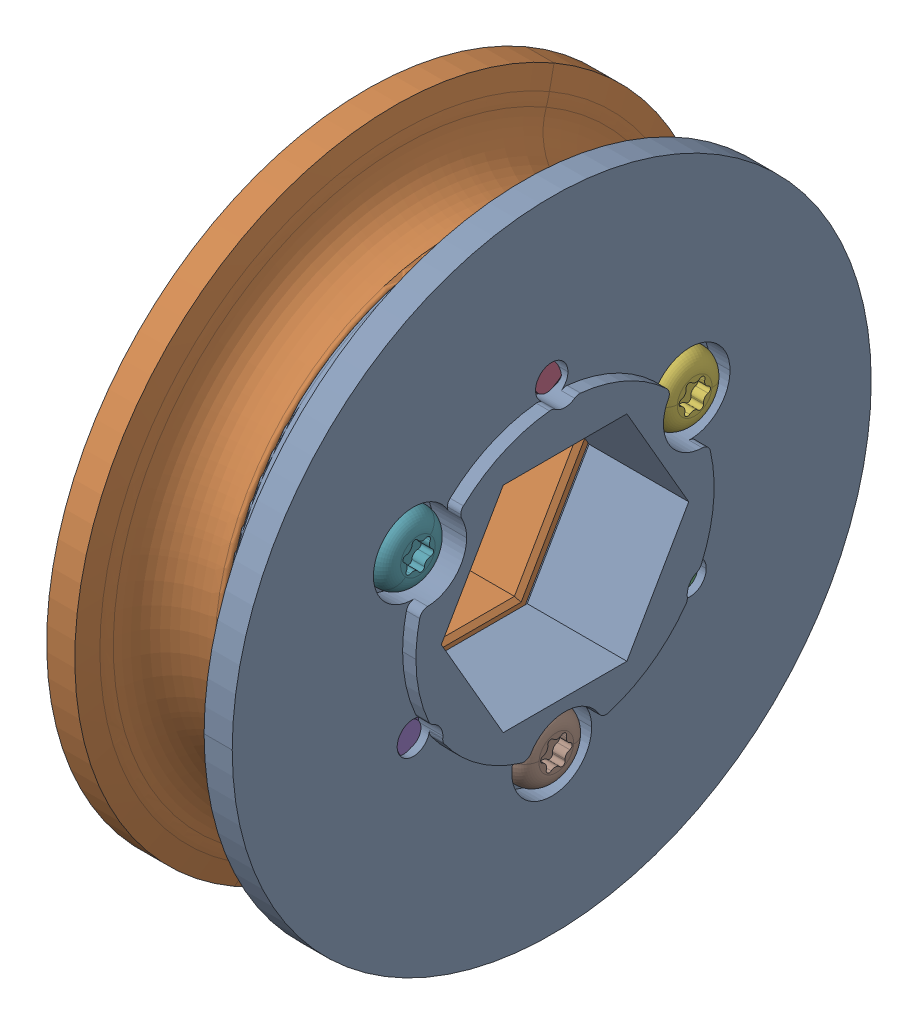
SolidWorks assembly WCP-0096 Rev6-7.step, configuration Default. Lengths in mm.
Overall size (12.65 52.05 52.05).
8 component instances, 2 part files, 0 mates.
Components (placement in the parent):
- WCP-0096-001 Rev6.step-1: WCP-0096-001 Rev6.step [Default] at origin size (7.57 38.1 38.1)
- WCP-0096-001 Rev6.step-2: WCP-0096-001 Rev6.step [Default] x (-1 0 0) z (0 0.866025 -0.5) size (7.57 38.1 38.1)
- WCP-0356 Rev1.step-1: WCP-0356 Rev1.step [Default] at (0.4817 -4.7625 -8.2489) x (0 -0.126969 0.991907) z (0 -0.991907 -0.126969) size (4.06 11.05 4.06)
- WCP-0356 Rev1.step-2: WCP-0356 Rev1.step [Default] at (0.4817 9.525 0) x (0 0.866766 0.498715) z (0 -0.498715 0.866766) size (4.06 11.05 4.06)
- WCP-0356 Rev1.step-3: WCP-0356 Rev1.step [Default] at (0.4817 -4.7625 8.2489) x (0 -0.994015 -0.109248) z (0 0.109248 -0.994015) size (4.06 11.05 4.06)
- WCP-0356 Rev1.step-4: WCP-0356 Rev1.step [Default] at (-0.4817 4.7625 -8.2489) x (0 -0.997555 0.069879) z (0 0.069879 0.997555) size (4.06 11.05 4.06)
- WCP-0356 Rev1.step-5: WCP-0356 Rev1.step [Default] at (-0.4817 4.7625 8.2489) x (0 -0.7202 -0.693767) z (0 -0.693767 0.7202) size (4.06 11.05 4.06)
- WCP-0356 Rev1.step-6: WCP-0356 Rev1.step [Default] at (-0.4817 -9.525 0) x (0 -0.997555 0.069879) z (0 0.069879 0.997555) size (4.06 11.05 4.06)
